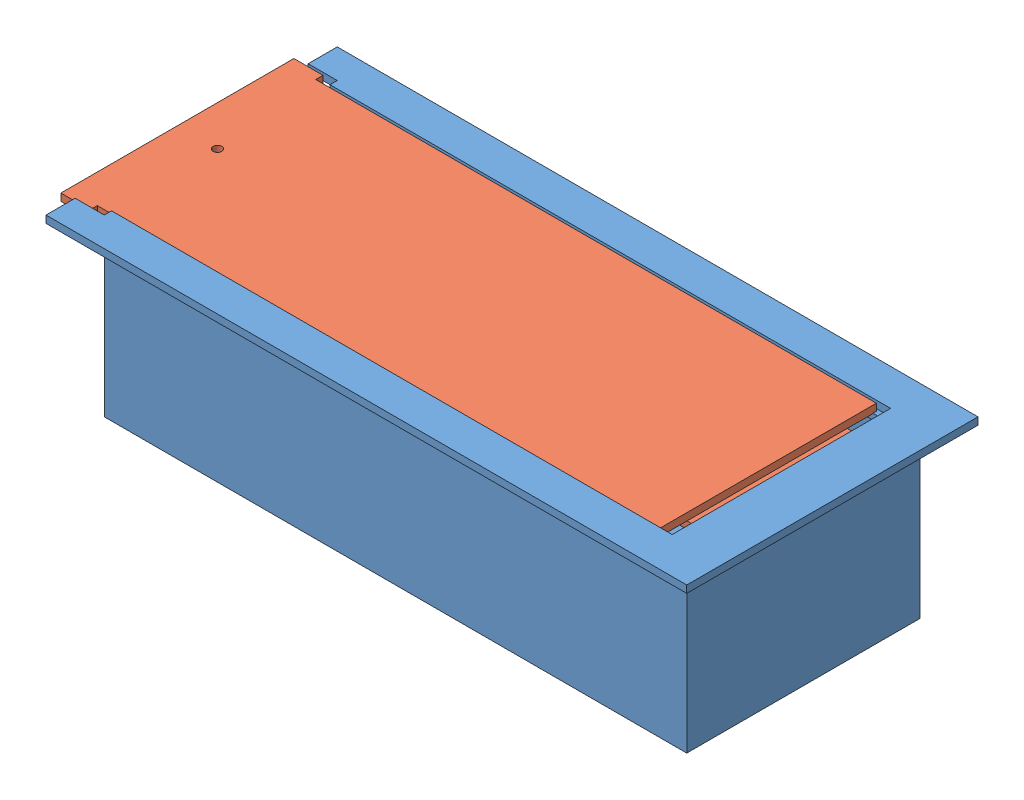
SolidWorks assembly Assem1, configuration Default. Lengths in mm.
Overall size (224.11 60 100).
2 component instances, 2 part files, 0 mates.
Components (placement in the parent):
- battery_housing-1: battery_housing [Default] at (-6.4425 123.2126 209.8922) size (220 60 100)
- lid-2: lid [Default] at (181.9495 180.5968 213.1752) x (-1 0 0) z (0 1 0) size (205.5 80 5)
